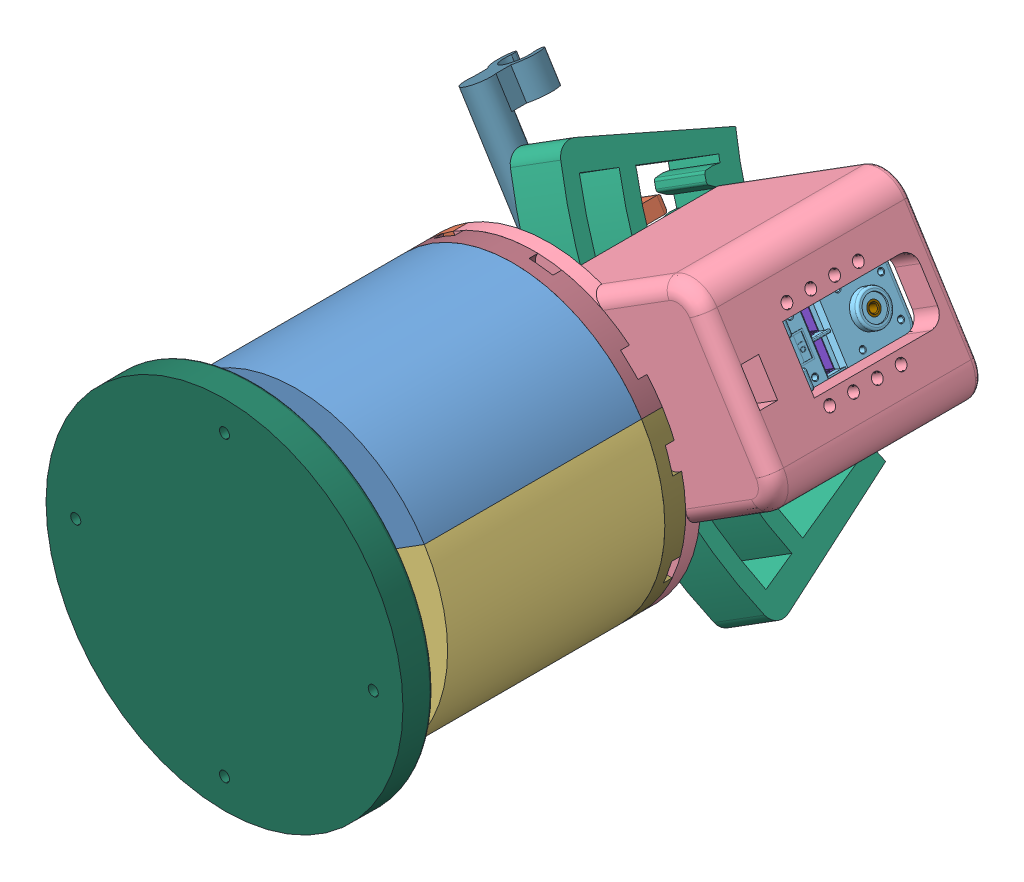
SolidWorks assembly neck, configuration Défaut. Lengths in mm.
Overall size (276.15 243.78 413.67).
74 component instances, 50 part files, 51 mates.
Components (placement in the parent):
- actuator_interface_3-1: actuator_interface_3 [Défaut] at (0 0 -18) x (0.532073 -0.846698 0) z (0 0 -1) size (99.5 102 78)
- actuator_interface_2-1: actuator_interface_2 [Défaut] at (0 0 -93.996) x (0.846698 0.532073 0) z (-0.532073 0.846698 0) size (35 70 102)
- actuator_interface_4-1: actuator_interface_4 [Défaut] at (0 0 -18) x (-0.532073 0.846698 0) z (0 0 -1) size (99.5 102 78)
- actuator_interface_1-1: actuator_interface_1 [Défaut] at (0 0 -114) x (-0.846698 -0.532073 0) z (0.532073 -0.846698 0) size (80 70 102)
- AX-18A-1: AX-18A [Défaut] at (45.7217 28.732 -112.0076) x (-0.532073 0.846698 0) z (-0.846698 -0.532073 0) size (32 50.04 40.32)
  - ASSY_DUMMY___^AX-18A-1: ASSY_DUMMY___^AX-18A [Défaut] at origin size (32 50.04 38.37) (virtual)
  - ASSY_GEAR-WHEEL___DUMMY^AX-18A-1: ASSY_GEAR-WHEEL___DUMMY^AX-18A [Défaut] at (0 0 -2) x (-1 0 0) z (0 0 1) size (6.5 6.5 5.51) (virtual)
  - DX124_SCREW-COVER___^AX-18A-1: DX124_SCREW-COVER___^AX-18A [Défaut] at (9.5 8.5 14.5) x (-1 0 0) z (0 1 0) size (3.5 30.7 3.5) (virtual)
  - DX124_SCREW-COVER___^AX-18A-2: DX124_SCREW-COVER___^AX-18A [Défaut] at (-9.5 8.5 14.5) x (-1 0 0) z (0 1 0) size (3.5 30.7 3.5) (virtual)
  - DX124_SCREW-COVER___^AX-18A-3: DX124_SCREW-COVER___^AX-18A [Défaut] at (10.5 -33 14.5) x (-1 0 0) z (0 1 0) size (3.5 30.7 3.5) (virtual)
  - DX124_SCREW-COVER___^AX-18A-4: DX124_SCREW-COVER___^AX-18A [Défaut] at (-10.5 -33 14.5) x (-1 0 0) z (0 1 0) size (3.5 30.7 3.5) (virtual)
  - 099990987____^AX-18A-1: 099990987____^AX-18A [Défaut] at (5.05 -15.19 -9.75) x (1 0 0) z (0 1 0) size (9.9 9.43 4.9) (virtual)
  - 099990987____^AX-18A-2: 099990987____^AX-18A [Défaut] at (-4.95 -15.19 -9.75) x (1 0 0) z (0 1 0) size (9.9 9.43 4.9) (virtual)
  - DC04_B01_INSERT_M3^AX-18A-1: DC04_B01_INSERT_M3^AX-18A [Défaut] at (0 0 -18.4) x (-1 0 0) z (0 1 0) size (4.98 7 4.98) (virtual)
  - DC04_B01_HORN2_DUMMY^AX-18A-1: DC04_B01_HORN2_DUMMY^AX-18A [Défaut] at (0 0 19.1) x (0 1 0) z (0 0 1) size (22 22 6.7) (virtual)
  - BHS_M2_6X8^AX-18A-1: BHS_M2_6X8^AX-18A [Défaut] at (0 0 19.55) x (0 1 0) z (1 0 0) size (5.5 9.6 5.5) (virtual)
- neck_axis-1: neck_axis [Défaut] at (-35.8296 0.6331 -91.786) x (0.491491 -0.782119 0.383049) z (0.846698 0.532073 0) size (5 5 105)
- neck_axis-2: neck_axis [Défaut] at (-14.9723 -32.5575 -91.786) x (0.491491 -0.782119 0.383049) z (0.846698 0.532073 0) size (5 5 105)
- ballBearing-1: ballBearing [Défaut] at (10.4286 -16.5953 -91.786) x (-0.846698 -0.532073 0) z (-0.371739 0.591555 0.715453) size (3.01 11 11)
  - ball1-1: ball1 [Défaut] at (1.5 3.0642 2.5712) size (1.96 2.07 2.07)
  - ball2-1: ball2 [Défaut] at (1.5 0.6946 3.9392) size (2.15 2.2 2.14)
  - ball3-1: ball3 [Défaut] at (1.5 -2 3.4641) size (1.97 2.11 2.11)
  - ball4-1: ball4 [Défaut] at (1.5 -3.7588 1.3681) size (2.08 2.02 2.1)
  - ball5-1: ball5 [Défaut] at (1.5 -3.7588 -1.3681) size (1.97 2.13 2.17)
  - ball6-1: ball6 [Défaut] at (1.5 -2 -3.4641) size (2.07 2.2 2.04)
  - ball7-1: ball7 [Défaut] at (1.5 0.6946 -3.9392) size (2.09 2.05 2.22)
  - ball8-1: ball8 [Défaut] at (1.5 3.0642 -2.5712) size (2.02 2.17 2.18)
  - ball9-1: ball9 [Défaut] at (1.5 4 0) size (2.21 2.22 2.24)
  - external_ring-1: external_ring [Défaut] at (1.5 0 0) size (3.01 11 11)
  - internal_ring-1: internal_ring [Défaut] at (1.5 0 0) size (3.01 6.8 6.8)
- ballBearing-2: ballBearing [Défaut] at (-10.4286 16.5953 -91.786) x (-0.846698 -0.532073 0) z (-0.363526 0.578486 -0.730208) size (3.01 11 11)
  - ball1-1: ball1 [Défaut] at (1.5 3.0642 2.5712) size (1.96 2.07 2.07)
  - ball2-1: ball2 [Défaut] at (1.5 0.6946 3.9392) size (2.15 2.2 2.14)
  - ball3-1: ball3 [Défaut] at (1.5 -2 3.4641) size (1.97 2.11 2.11)
  - ball4-1: ball4 [Défaut] at (1.5 -3.7588 1.3681) size (2.08 2.02 2.1)
  - ball5-1: ball5 [Défaut] at (1.5 -3.7588 -1.3681) size (1.97 2.13 2.17)
  - ball6-1: ball6 [Défaut] at (1.5 -2 -3.4641) size (2.07 2.2 2.04)
  - ball7-1: ball7 [Défaut] at (1.5 0.6946 -3.9392) size (2.09 2.05 2.22)
  - ball8-1: ball8 [Défaut] at (1.5 3.0642 -2.5712) size (2.02 2.17 2.18)
  - ball9-1: ball9 [Défaut] at (1.5 4 0) size (2.21 2.22 2.24)
  - external_ring-1: external_ring [Défaut] at (1.5 0 0) size (3.01 11 11)
  - internal_ring-1: internal_ring [Défaut] at (1.5 0 0) size (3.01 6.8 6.8)
- rack_pinion-1: rack_pinion [Défaut] at (-0.0372 0.0592 -246.5526) x (0.53176 -0.8462 -0.034291) z (0.846698 0.532073 0) size (127.33 287 240)
- sprocket_2-1: sprocket_2 [Défaut] x (0.532073 -0.846698 0) z (0 0 -1) size (22 22 10)
- sprocket_1-1: sprocket_1 [Défaut] at (0 0 -15) x (-0.532073 0.846698 0) z (0 0 1) size (22 22 10)
- DYNAMIXEL AX-12A-1: DYNAMIXEL AX-12A [Défaut] at (0 0 -36) x (0.846698 0.532073 0) z (0 0 1) size (50 32 40.55)
  - AX-12A-01-1: AX-12A-01 [Défaut] at origin size (48.5 26 22)
  - AX-12A-02-1: AX-12A-02 [Défaut] at (0 0 13.5) size (50 32 8)
  - AX-12A-03-1: AX-12A-03 [Défaut] at (0 0 -13.5) x (1 0 0) z (0 0 -1) size (50 32 8)
  - AX-12A-04-1: AX-12A-04 [Défaut] at (0 0 21) size (22 22 6.7)
  - SetScrew-1: SetScrew [Défaut] at (33 10.4 14.5) x (0.31498 0.949098 0) z (0 0 -1) size (3.3 3.3 29.44)
  - SetScrew-2: SetScrew [Défaut] at (-9 9.25 14.5) x (0.31498 0.949098 0) z (0 0 -1) size (3.3 3.3 29.44)
  - SetScrew-3: SetScrew [Défaut] at (-9 -9.25 14.5) x (-0.958559 0.284893 0) z (0 0 -1) size (3.3 3.3 29.44)
  - SetScrew-4: SetScrew [Défaut] at (33 -10.4 14.5) x (0.31498 0.949098 0) z (0 0 -1) size (3.3 3.3 29.44)
  - M2.5 x 8-1: M2.5 x 8 [Défaut] at (0 0 21.6) x (0 0 -1) z (1 0 0) size (10.05 5 5)
- actuator_holder-1: actuator_holder [Défaut] at origin size (120 120 45)
- actuator_axis-1: actuator_axis [Défaut] at (27.9918 17.5903 -112.0076) x (-0.529316 0.84231 -0.10168) z (-0.846698 -0.532073 0) size (22 22 62.75)
- ballBearing2-1: ballBearing2 [Défaut] at (-25.1385 -15.7973 -112.0076) x (0.846698 0.532073 0) z (0.023473 -0.037354 0.999026) size (5.01 19 19)
  - ball-1: ball [Défaut] at (2.5 6.0991 3.9196) size (3.2 3.01 3.02)
  - ball_2-1: ball_2 [Défaut] at (2.5 3.0118 6.5948) size (3.23 3.28 3.31)
  - ball_3-1: ball_3 [Défaut] at (2.5 -1.0318 7.1762) size (3.31 3.03 3.32)
  - ball_4-1: ball_4 [Défaut] at (2.5 -4.7477 5.4792) size (3.18 3.13 3.12)
  - ball_5-1: ball_5 [Défaut] at (2.5 -6.9563 2.0426) size (3.11 3.23 3.11)
  - ball_6-1: ball_6 [Défaut] at (2.5 -6.9563 -2.0426) size (3.2 3.24 3.25)
  - ball_7-1: ball_7 [Défaut] at (2.5 -4.7477 -5.4792) size (3.13 3.32 3.2)
  - ball_8-1: ball_8 [Défaut] at (2.5 -1.0318 -7.1762) size (3.23 3.19 3.29)
  - ball_9-1: ball_9 [Défaut] at (2.5 3.0118 -6.5948) size (3.19 2.92 2.97)
  - ball_10-1: ball_10 [Défaut] at (2.5 6.0991 -3.9196) size (3.19 2.92 2.97)
  - ball_11-1: ball_11 [Défaut] at (2.5 7.25 0) size (3.28 3.11 3.26)
  - external_bearing_ring-1: external_bearing_ring [Défaut] at (2.5 0 0) size (5 19 19)
  - internal_bearing_ring-1: internal_bearing_ring [Défaut] at (2.5 0 0) size (5.01 12.6 12.6)
- actuator_interface_3_handle-1: actuator_interface_3_handle [Défaut] at (0 0 -93) x (-0.532073 0.846698 0) z (0 0 -1) size (51 102 7)
- actuator_interface_4_handle-1: actuator_interface_4_handle [Défaut] at (0 0 -93) x (0.532073 -0.846698 0) z (0 0 1) size (121.83 102 7)
- handle_microphone-1: handle_microphone [Défaut] at (-61.0037 21.8987 -111.996) x (0.846698 0.532073 0) z (-0.532073 0.846698 0) size (20.05 24.31 80)
Mates (geometry in assembly coordinates):
- Coïncidente74: coincident anti-aligned: plane of actuator_interface_4-1 through (-38.9481 -24.4754 -52) normal (-0.532073 0.846698 0); plane of actuator_interface_3-1 through (38.9481 24.4754 -52) normal (0.532073 -0.846698 0)
- Coaxiale26: concentric aligned: cylinder of actuator_interface_4-1 through (0 0 -52) axis (0 0 1) radius 51; cylinder of actuator_interface_3-1 through (0 0 -52) axis (0 0 1) radius 51
- Coaxiale5: concentric anti-aligned: cylinder of actuator_holder-1 through (0 0 15) axis (0 0 -1) radius 45; cylinder of actuator_interface_4-1 through (0 0 -52) axis (0 0 1) radius 46
- Coïncidente59: coincident aligned: plane of rack_pinion-1 through (-0.0372 0.0592 -246.5526) normal (0.846698 0.532073 0); plane of actuator_interface_4-1
- Parallèle7: parallel aligned: plane of sprocket_1-1 through (-3.7245 5.9269 -5) normal (-0.532073 0.846698 0); plane of actuator_interface_4-1 through (-38.9481 -24.4754 -52) normal (-0.532073 0.846698 0)
- Parallèle9: parallel anti-aligned: plane of DYNAMIXEL AX-12A-1/AX-12A-01-1 through (36.128 7.3495 -47) normal (0.532073 -0.846698 0); plane of actuator_interface_4-1 through (-38.9481 -24.4754 -52) normal (-0.532073 0.846698 0)
- Coïncidente18: coincident anti-aligned: plane of actuator_interface_1-1 through (59.2689 37.2451 -164) normal (-0.846698 -0.532073 0); plane of AX-18A-1/ASSY_DUMMY___^AX-18A-1 through (59.2689 37.2451 -112.0076) normal (0.846698 0.532073 0)
- Coïncidente19: coincident: plane of actuator_interface_1-1 through (0 0 -114) normal (0.532073 -0.846698 0); point of AX-18A-1/ASSY_DUMMY___^AX-18A-1
- Parallèle2: parallel aligned: plane of AX-18A-1/ASSY_DUMMY___^AX-18A-1 through (68.7259 27.8343 -123.5076) normal (0.532073 -0.846698 0); plane of actuator_interface_1-1 through (-13.8339 22.0142 -164) normal (0.532073 -0.846698 0)
- Coïncidente56: coincident anti-aligned: plane of actuator_interface_1-1 through (73.931 23.3102 -91.786) normal (-0.846698 -0.532073 0); plane of neck_axis-1 through (53.0737 56.5008 -91.786) normal (0.846698 0.532073 0)
- Coaxiale19: concentric aligned: cylinder of actuator_interface_1-1 through (73.931 23.3102 -91.786) axis (-0.846698 -0.532073 0) radius 2.5; cylinder of neck_axis-2 through (73.931 23.3102 -91.786) axis (-0.846698 -0.532073 0) radius 2.5
- Coaxiale20: concentric aligned: cylinder of actuator_interface_1-1 through (53.0737 56.5008 -91.786) axis (-0.846698 -0.532073 0) radius 2.5; cylinder of neck_axis-1 through (53.0737 56.5008 -91.786) axis (-0.846698 -0.532073 0) radius 2.5
- Coïncidente30: coincident anti-aligned: plane of AX-18A-1/DC04_B01_HORN2_DUMMY^AX-18A-1 through (27.9918 17.5903 -112.0076) normal (-0.846698 -0.532073 0); plane of actuator_axis-1 through (27.9918 17.5903 -112.0076) normal (0.846698 0.532073 0)
- Coaxiale8: concentric anti-aligned: cylinder of AX-18A-1/DC04_B01_HORN2_DUMMY^AX-18A-1 through (29.5498 18.5694 -112.0076) axis (-0.846698 -0.532073 0) radius 11; cylinder of actuator_axis-1 through (23.7584 14.93 -112.0076) axis (0.846698 0.532073 0) radius 11
- Coaxiale22: concentric anti-aligned: cylinder of neck_axis-1 through (53.0737 56.5008 -91.786) axis (-0.846698 -0.532073 0) radius 2.5; cylinder of ballBearing-2/internal_ring-1 through (-12.8417 15.0789 -91.786) axis (0.846698 0.532073 0) radius 2.5
- Coaxiale21: concentric anti-aligned: cylinder of neck_axis-2 through (73.931 23.3102 -91.786) axis (-0.846698 -0.532073 0) radius 2.5; cylinder of ballBearing-1/internal_ring-1 through (8.0155 -18.1117 -91.786) axis (0.846698 0.532073 0) radius 2.5
- Coïncidente57: coincident aligned: plane of ballBearing-1/internal_ring-1 through (8.8973 -19.7968 -89.9346) normal (-0.846698 -0.532073 0); plane of ballBearing-2/internal_ring-1 through (-13.9983 16.6375 -89.9755) normal (-0.846698 -0.532073 0)
- Distance11: distance = 0.4885 mm: cylinder of rack_pinion-1 through (8.4298 5.3799 -246.5526) axis (-0.846698 -0.532073 0) radius 162; cylinder of ballBearing-1/external_ring-1 through (7.8885 -18.1915 -91.786) axis (0.846698 0.532073 0) radius 5.5
- Contr.Engrenages6: gear = 11 : 240 mm: cylinder of rack_pinion-1 through (8.4298 5.3799 -246.5526) axis (-0.846698 -0.532073 0) radius 120; cylinder of ballBearing-1/external_ring-1 through (7.8885 -18.1915 -91.786) axis (0.846698 0.532073 0) radius 5.5
- Coïncidente58: coincident anti-aligned: plane of rack_pinion-1 through (-0.0372 0.0592 -246.5526) normal (0.846698 0.532073 0); plane of ballBearing-2
- Distance10: distance = 0.494 mm: cylinder of ballBearing-2/external_ring-1 through (-12.9687 14.9991 -91.786) axis (0.846698 0.532073 0) radius 5.5; cylinder of rack_pinion-1 through (8.4298 5.3799 -246.5526) axis (-0.846698 -0.532073 0) radius 150
- Contr.Engrenages7: gear = 240 : 11 mm: cylinder of ballBearing-2/external_ring-1 through (-12.9687 14.9991 -91.786) axis (0.846698 0.532073 0) radius 5.5; cylinder of rack_pinion-1 through (8.4298 5.3799 -246.5526) axis (-0.846698 -0.532073 0) radius 120
- Contr.Engrenages3: gear = 15 : 245 mm: circle of rack_pinion-1; circle of actuator_axis-1
- Distance3: distance = 5 mm: cylinder of actuator_axis-1 through (0.1326 132 36.9398) axis (-0.00359 0 -0.999994) radius 5; cylinder of rack_pinion-1 through (3.1472 262.9622 -3.0713) axis (0.00359 0 0.999994) radius 142
- Parallèle6: parallel aligned: plane of actuator_axis-1 through (-25.1385 -15.7973 -112.0076) normal (-0.846698 -0.532073 0); plane of rack_pinion-1 through (-8.5042 -5.2616 -246.5526) normal (-0.846698 -0.532073 0)
- Contr.Engrenages4: gear = 245 : 15 mm: cylinder of actuator_axis-1 through (-25.1385 -15.7973 -112.0076) axis (0.846698 0.532073 0) radius 5; cylinder of rack_pinion-1 through (8.4298 5.3799 -246.5526) axis (-0.846698 -0.532073 0) radius 120
- Coïncidente63: coincident anti-aligned: plane of actuator_holder-1 through (0 0 0) normal (0 0 -1); plane of sprocket_2-1 through (0 0 0) normal (0 0 1)
- Coaxiale24: concentric anti-aligned: cylinder of actuator_holder-1 through (0 0 15) axis (0 0 -1) radius 45; cylinder of sprocket_2-1 through (0 0 -5) axis (0 0 1) radius 11
- Coïncidente70: coincident anti-aligned: plane of sprocket_1-1 through (0 0 -5) normal (0 0 1); plane of sprocket_2-1 through (0 0 -5) normal (0 0 -1)
- Parallèle10: parallel anti-aligned: plane of sprocket_1-1 through (1.3302 -2.1167 -5) normal (-0.532073 0.846698 0); plane of sprocket_2-1 through (-7.9196 -7.6341 -10) normal (0.532073 -0.846698 0)
- Coïncidente4: coincident anti-aligned: plane of DYNAMIXEL AX-12A-1/AX-12A-04-1 through (-3.4069 -14.9299 -15) normal (0 0 1); plane of sprocket_1-1 through (0 0 -15) normal (0 0 -1)
- Coaxiale2: concentric aligned: cylinder of DYNAMIXEL AX-12A-1/AX-12A-04-1 through (0 0 -15.3) axis (0 0 -1) radius 11; cylinder of sprocket_1-1 through (0 0 -10) axis (0 0 -1) radius 11
- Coaxiale1: concentric anti-aligned: circle of DYNAMIXEL AX-12A-1/AX-12A-04-1; cylinder of actuator_holder-1 through (0 0 15) axis (0 0 -1) radius 45
- Contr.Engrenages8: gear = 240 : 19 mm: cylinder of ballBearing2-1/external_bearing_ring-1 through (-20.905 -13.1369 -112.0076) axis (-0.846698 -0.532073 0) radius 9.5; cylinder of rack_pinion-1 through (8.4298 5.3799 -246.5526) axis (-0.846698 -0.532073 0) radius 120
- Coaxiale40: concentric anti-aligned: cylinder of actuator_axis-1 through (-25.1385 -15.7973 -112.0076) axis (0.846698 0.532073 0) radius 5; cylinder of ballBearing2-1/internal_bearing_ring-1 through (-21.159 -13.2965 -112.0076) axis (-0.846698 -0.532073 0) radius 5
- Coïncidente154: coincident aligned: circle of actuator_axis-1; plane of ballBearing2-1/internal_bearing_ring-1 through (-28.4341 -10.5528 -111.7341) normal (-0.846698 -0.532073 0)
- Coïncidente159: coincident anti-aligned: plane of actuator_interface_3-1 through (0 0 -52) normal (0 0 -1); plane of actuator_interface_3_handle-1 through (0 0 -52) normal (0 0 1)
- Coïncidente160: coincident anti-aligned: plane of actuator_interface_4-1 through (0 0 -52) normal (0 0 -1); plane of actuator_interface_4_handle-1 through (0 0 -52) normal (0 0 1)
- Coaxiale56: concentric aligned: circle of actuator_interface_4-1; circle of actuator_interface_1-1
- Coïncidente163: coincident aligned: line of actuator_interface_3_handle-1 through (28.6184 17.9841 -59) axis (0.846698 0.532073 0); line of actuator_interface_4_handle-1 through (28.6184 17.9841 -59) axis (0.846698 0.532073 0)
- Coïncidente167: coincident anti-aligned: plane of actuator_interface_1-1 through (0.0026 0.0016 -59) normal (0 0 1); plane of actuator_interface_3_handle-1 through (0 0 -59) normal (0 0 -1)
- Coaxiale57: concentric aligned: circle of actuator_interface_2-1; circle of neck_axis-2
- Coaxiale58: concentric anti-aligned: circle of sprocket_1-1; circle of DYNAMIXEL AX-12A-1/AX-12A-04-1
- Coïncidente170: coincident anti-aligned: plane of sprocket_1-1 through (0 0 -15) normal (0 0 -1); plane of DYNAMIXEL AX-12A-1/AX-12A-04-1 through (-3.4069 -14.9299 -15) normal (0 0 1)
- Coaxiale60: concentric anti-aligned: circle of actuator_interface_4-1; circle of actuator_interface_3_handle-1
- Coaxiale61: concentric anti-aligned: circle of actuator_interface_4-1; circle of actuator_interface_3_handle-1
- Coïncidente171: coincident anti-aligned: plane of DYNAMIXEL AX-12A-1/AX-12A-03-1 through (23.7701 32.6532 -52) normal (0 0 -1); plane of actuator_interface_3_handle-1 through (0 0 -52) normal (0 0 1)
- Coaxiale62: concentric aligned: circle of actuator_interface_3-1; circle of actuator_interface_4_handle-1
- Coïncidente173: coincident anti-aligned: plane of actuator_interface_2-1 through (-29.6344 -18.6226 -128.996) normal (-0.846698 -0.532073 0); plane of handle_microphone-1 through (-24.8458 -26.2429 -116.996) normal (0.846698 0.532073 0)
- Coaxiale63: concentric aligned: circle of actuator_interface_2-1; circle of handle_microphone-1
- Coaxiale64: concentric aligned: circle of actuator_interface_2-1; circle of handle_microphone-1
